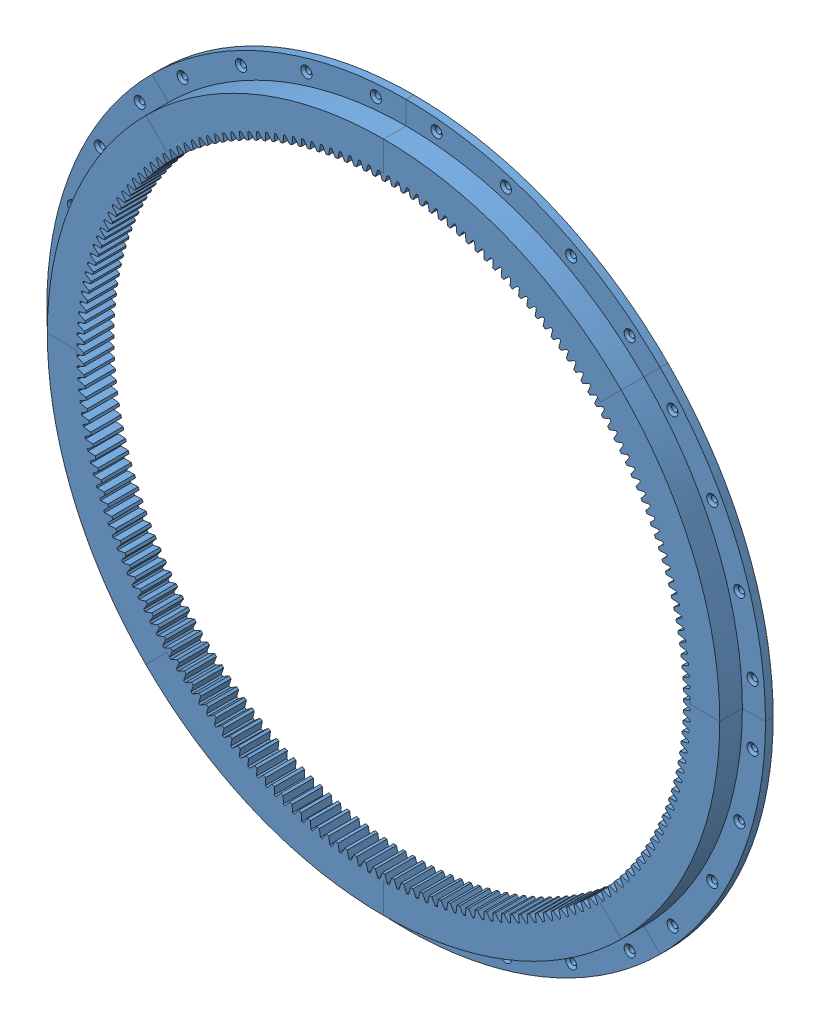
SolidWorks assembly Assem2, configuration Default. Lengths in mm.
Overall size (715.94 715.94 25).
8 component instances, 1 part files, 21 mates.
Components (placement in the parent):
- Ring Gear Segment-1: Ring Gear Segment [2696N41] at (61.3478 -39.6039 275.3384) size (212.88 117.56 25)
- Ring Gear Segment-2: Ring Gear Segment [2696N41] at (61.3478 -39.6039 275.3384) x (0.707107 -0.707107 0) z (0 0 1) size (212.88 117.56 25)
- Ring Gear Segment-3: Ring Gear Segment [2696N41] at (61.3478 -39.6039 275.3384) x (-1 0 0) z (0 0 1) size (212.88 117.56 25)
- Ring Gear Segment-4: Ring Gear Segment [2696N41] at (61.3478 -39.6039 275.3384) x (-0.707107 0.707107 0) z (0 0 1) size (212.88 117.56 25)
- Ring Gear Segment-5: Ring Gear Segment [2696N41] at (61.3478 -39.6039 275.3384) x (0 1 0) z (0 0 1) size (212.88 117.56 25)
- Ring Gear Segment-6: Ring Gear Segment [2696N41] at (61.3478 -39.6039 275.3384) x (0.707107 0.707107 0) z (0 0 1) size (212.88 117.56 25)
- Ring Gear Segment-7: Ring Gear Segment [2696N41] at (61.3478 -39.6039 275.3384) x (0 -1 0) z (0 0 1) size (212.88 117.56 25)
- Ring Gear Segment-8: Ring Gear Segment [2696N41] at (61.3478 -39.6039 275.3384) x (-0.707107 -0.707107 0) z (0 0 1) size (212.88 117.56 25)
Mates (geometry in assembly coordinates):
- Coincident1: coincident anti-aligned: plane of Ring Gear Segment-1 through (61.3478 -39.6039 275.3384) normal (0.707107 -0.707107 0); plane of Ring Gear Segment-2 through (61.3478 -39.6039 275.3384) normal (-0.707107 0.707107 0)
- Concentric1: concentric anti-aligned: cylinder of Ring Gear Segment-1 through (61.3478 -39.6039 300.3384) axis (0 0 1) radius 253.125; cylinder of Ring Gear Segment-2 through (61.3478 -39.6039 308.8363) axis (0 0 -1) radius 253.125
- Coincident2: coincident aligned: plane of Ring Gear Segment-1 through (240.3342 139.3825 300.3384) normal (0 0 1); plane of Ring Gear Segment-2 through (314.4728 -39.6039 300.3384) normal (0 0 1)
- Coincident3: coincident anti-aligned: plane of Ring Gear Segment-2 through (61.3478 -39.6039 275.3384) normal (0 -1 0); plane of Ring Gear Segment-7 through (61.3478 -39.6039 275.3384) normal (0 1 0)
- Concentric2: concentric anti-aligned: cylinder of Ring Gear Segment-2 through (61.3478 -39.6039 300.3384) axis (0 0 1) radius 253.125; cylinder of Ring Gear Segment-7 through (61.3478 -39.6039 308.8363) axis (0 0 -1) radius 253.125
- Coincident4: coincident aligned: plane of Ring Gear Segment-2 through (314.4728 -39.6039 300.3384) normal (0 0 1); plane of Ring Gear Segment-7 through (240.3342 -218.5903 300.3384) normal (0 0 1)
- Coincident5: coincident: plane of Ring Gear Segment-7 through (61.3478 -39.6039 275.3384) normal (-0.707107 -0.707107 0); plane of Ring Gear Segment-8 through (61.3478 -39.6039 77.926) normal (0.707107 0.707107 0)
- Concentric3: concentric: cylinder of Ring Gear Segment-7 through (61.3478 -39.6039 300.3384) axis (0 0 1) radius 253.125; cylinder of Ring Gear Segment-8 through (61.3478 -39.6039 111.4239) axis (0 0 -1) radius 253.125
- Coincident7: coincident aligned: plane of Ring Gear Segment-7 through (240.3342 -218.5903 300.3384) normal (0 0 1); plane of Ring Gear Segment-8 through (61.3478 -292.7289 300.3384) normal (0 0 1)
- Coincident8: coincident: plane of Ring Gear Segment-3 through (61.3478 -39.6039 -60.0916) normal (1 0 0); plane of Ring Gear Segment-8 through (61.3478 -39.6039 275.3384) normal (-1 0 0)
- Concentric4: concentric: cylinder of Ring Gear Segment-3 through (61.3478 -39.6039 -26.5937) axis (0 0 -1) radius 253.125; cylinder of Ring Gear Segment-8 through (61.3478 -39.6039 300.3384) axis (0 0 1) radius 253.125
- Coincident9: coincident aligned: plane of Ring Gear Segment-3 through (-117.6386 -218.5903 300.3384) normal (0 0 1); plane of Ring Gear Segment-8 through (61.3478 -292.7289 300.3384) normal (0 0 1)
- Coincident10: coincident: plane of Ring Gear Segment-3 through (61.3478 -39.6039 275.3384) normal (-0.707107 0.707107 0); plane of Ring Gear Segment-4 through (61.3478 -39.6039 275.3384) normal (0.707107 -0.707107 0)
- Concentric5: concentric: cylinder of Ring Gear Segment-3 through (61.3478 -39.6039 300.3384) axis (0 0 1) radius 253.125; cylinder of Ring Gear Segment-4 through (61.3478 -39.6039 308.8363) axis (0 0 -1) radius 253.125
- Coincident11: coincident aligned: plane of Ring Gear Segment-3 through (-117.6386 -218.5903 300.3384) normal (0 0 1); plane of Ring Gear Segment-4 through (-191.7772 -39.6039 300.3384) normal (0 0 1)
- Coincident12: coincident: plane of Ring Gear Segment-4 through (61.3478 -39.6039 275.3384) normal (0 1 0); plane of Ring Gear Segment-5 through (61.3478 -39.6039 275.3384) normal (0 -1 0)
- Concentric6: concentric: cylinder of Ring Gear Segment-4 through (61.3478 -39.6039 300.3384) axis (0 0 1) radius 253.125; cylinder of Ring Gear Segment-5 through (61.3478 -39.6039 308.8363) axis (0 0 -1) radius 253.125
- Coincident13: coincident aligned: plane of Ring Gear Segment-4 through (-191.7772 -39.6039 300.3384) normal (0 0 1); plane of Ring Gear Segment-5 through (-117.6386 139.3825 300.3384) normal (0 0 1)
- Coincident14: coincident: plane of Ring Gear Segment-5 through (61.3478 -39.6039 275.3384) normal (0.707107 0.707107 0); plane of Ring Gear Segment-6 through (61.3478 -39.6039 275.3384) normal (-0.707107 -0.707107 0)
- Concentric7: concentric: cylinder of Ring Gear Segment-5 through (61.3478 -39.6039 300.3384) axis (0 0 1) radius 253.125; cylinder of Ring Gear Segment-6 through (61.3478 -39.6039 308.8363) axis (0 0 -1) radius 253.125
- Coincident15: coincident aligned: plane of Ring Gear Segment-5 through (-117.6386 139.3825 300.3384) normal (0 0 1); plane of Ring Gear Segment-6 through (61.3478 213.5211 300.3384) normal (0 0 1)
